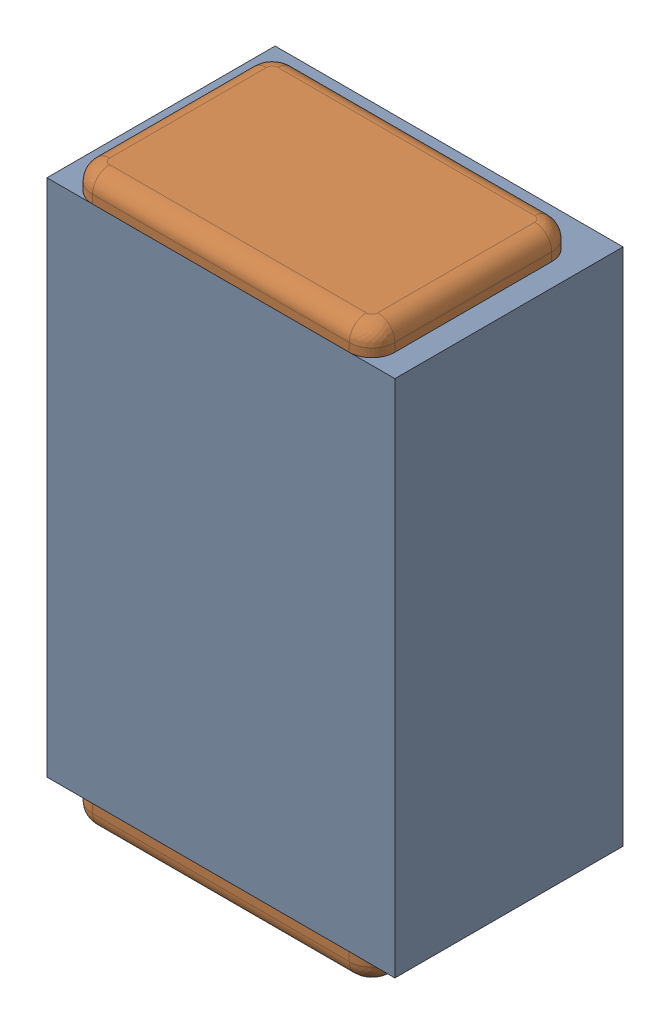
SolidWorks assembly C25, configuration Default. Lengths in mm.
Overall size (0.61 1 0.4).
3 component instances, 2 part files, 0 mates.
Components (placement in the parent):
- 1088881848-1: 1088881848 [Default] at (5.175 44.225 -2.044) size (0.61 0.91 0.4)
  - Extruded-1-1: Extruded-1 [Default] at origin size (0.61 0.91 0.4)
- C0402-1: C0402 [Default] at (5.1749 44.2249 -1.644) x (0 -1 0) z (1 0 0) size (1 0.36 0.54)
